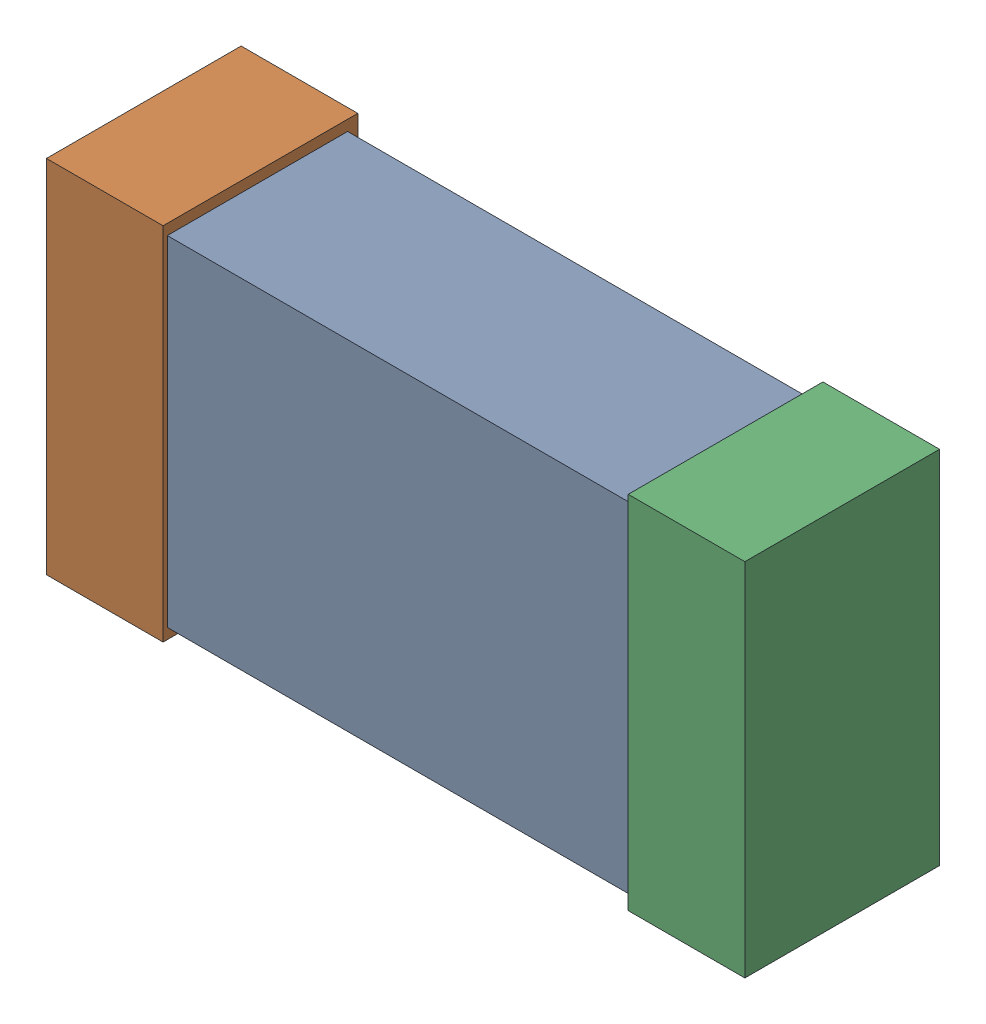
SolidWorks assembly R13, configuration Default. Lengths in mm.
Overall size (1.65 0.85 0.46).
6 component instances, 2 part files, 0 mates.
Components (placement in the parent):
- 432120720_17-1: 432120720_17 [Default] at (31.0959 12.0949 0.025) size (1.5 0.8 0.42)
  - Extruded (12)-1: Extruded (12) [Default] at origin size (1.5 0.8 0.42)
- 432120464_36-1: 432120464_36 [Default] at (30.4101 12.0949 0.001) size (0.28 0.85 0.46)
  - Extruded (11)-1: Extruded (11) [Default] at origin size (0.28 0.85 0.46)
- 432120464_37-1: 432120464_37 [Default] at (31.7816 12.0949 0.001) size (0.28 0.85 0.46)
  - Extruded (11)-1: Extruded (11) [Default] at origin size (0.28 0.85 0.46)
